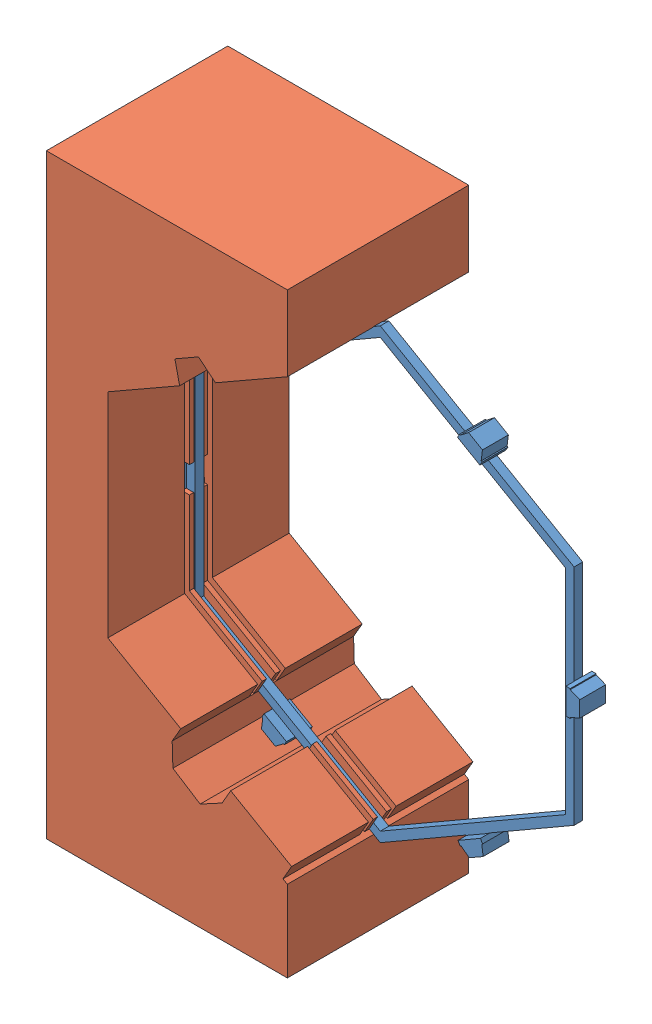
SolidWorks assembly RingLightToolAss, configuration Default. Lengths in mm.
Overall size (55.54 68.99 21).
2 component instances, 2 part files, 0 mates.
Components (placement in the parent):
- LEDRing-1: LEDRing [Default] at (-28.4736 11.0624 7.0095) size (53.7 58.31 3)
- LedRingJig-1: LedRingJig [Default] at (-28.4736 11.0624 7.0095) x (-1 0 0) z (0 0 -1) size (28.39 68.99 21)
